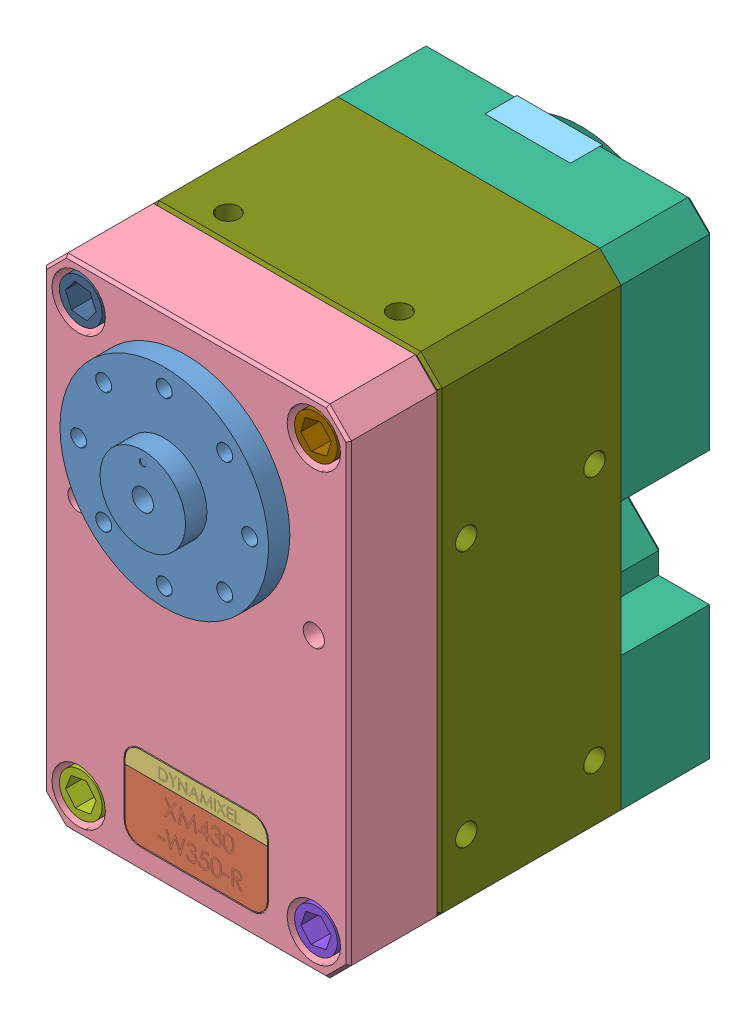
SolidWorks assembly XM430-W350-R, configuration Default. Lengths in mm.
Overall size (28.5 46.5 41).
17 component instances, 16 part files, 0 mates.
Components (placement in the parent):
- XM430-W350-R.step-1: XM430-W350-R.step [Default] at origin size (28.5 46.5 41)
  - Part 1.step-1: Part 1.step [Default] at (-0.4867 -0.6755 -0.5918) size (19.5 19.5 4)
  - Part 2.step-1: Part 2.step [Default] at (-0.4867 -0.6755 -0.5918) size (13.3 5.9 0.1)
  - Part 3.step-1: Part 3.step [Default] at (-0.4867 -0.6755 -0.5918) size (13.3 1.9 0.1)
  - Part 4.step-1: Part 4.step [Default] at (-0.4867 -0.6755 -0.5918) size (28.5 46.5 8.5)
  - Part 5.step-1: Part 5.step [Default] at (-0.4867 -0.6755 -0.5918) size (8 1.5 3)
  - Part 6.step-1: Part 6.step [Default] at (-0.4867 -0.6755 -0.5918) size (28.5 46.5 8.5)
  - Part 7.step-1: Part 7.step [Default] at (-0.4867 -0.6755 -0.5918) size (4 4 3.8)
  - Part 8.step-1: Part 8.step [Default] at (-0.4867 -0.6755 -0.5918) size (4 4 3.8)
  - Part 9.step-1: Part 9.step [Default] at (-0.4867 -0.6755 -0.5918) size (4 4 3.8)
  - Part 10.step-1: Part 10.step [Default] at (-0.4867 -0.6755 -0.5918) size (4 4 3.8)
  - Part 11.step-1: Part 11.step [Default] at (-0.4867 -0.6755 -0.5918) size (4 4 3.8)
  - Part 12.step-1: Part 12.step [Default] at (-0.4867 -0.6755 -0.5918) size (4 4 3.8)
  - Part 13.step-1: Part 13.step [Default] at (-0.4867 -0.6755 -0.5918) size (4 4 3.8)
  - Part 14.step-1: Part 14.step [Default] at (-0.4867 -0.6755 -0.5918) size (4 4 3.8)
  - Part 15.step-1: Part 15.step [Default] at (-0.4867 -0.6755 -0.5918) size (19.5 19.5 2)
  - Part 16.step-1: Part 16.step [Default] at (-0.4867 -0.6755 -0.5918) size (28.5 46.5 17)
